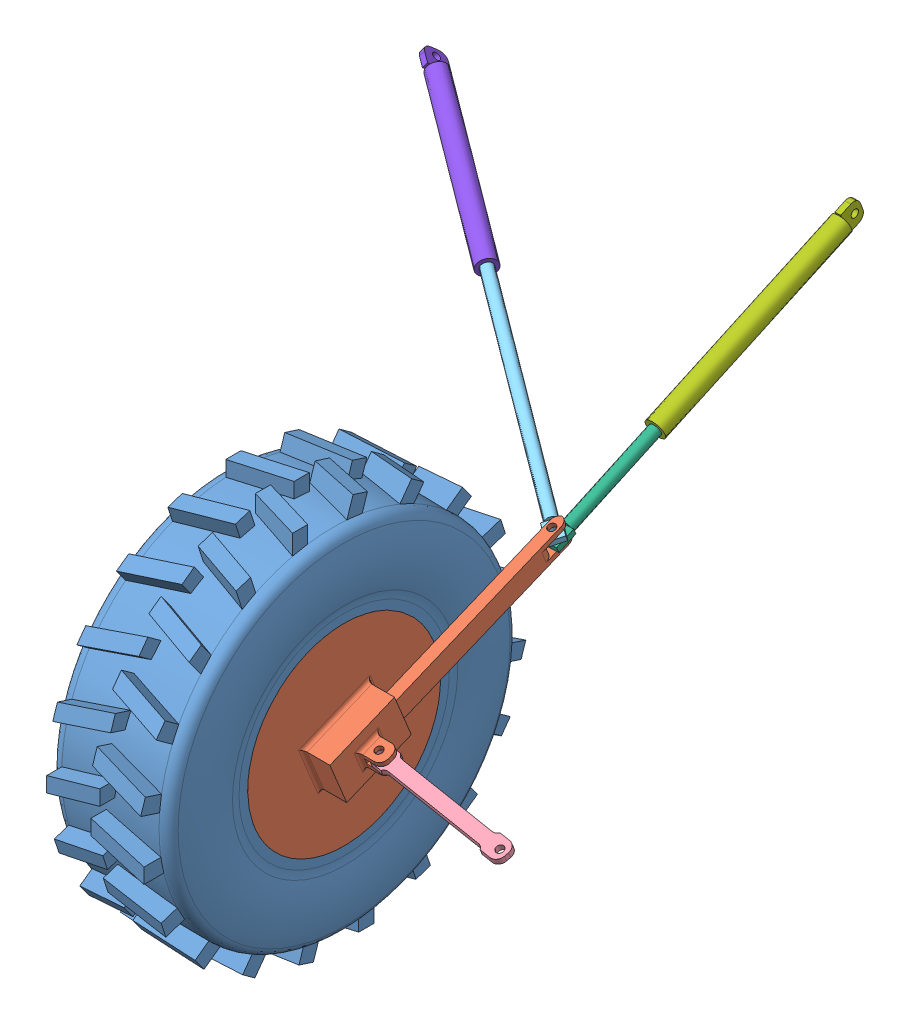
SolidWorks assembly Only tyre part assembly, configuration Default. Lengths in mm.
Overall size (145.33 108.44 186.61).
8 component instances, 8 part files, 12 mates.
Components (placement in the parent):
- Tyre-1: Tyre [Default] at (-1.433 57.6612 95.7909) size (33.63 101.74 101.74)
- Inner Rim 1-1: Inner Rim 1 [Default] at (8.2992 57.6612 95.7909) x (0 0.381849 -0.924225) z (0 -0.924225 -0.381849) size (84.64 19 50.96)
- Outer Rim Part-1: Outer Rim Part [Default] at (-17.1653 57.6612 95.7909) x (0 -0.924225 -0.381849) z (1 0 0) size (50.96 50.96 8)
- Connecting Rod 2-1: Connecting Rod 2 [Default] at (42.1511 56.0879 97.6348) x (0.991767 -0.048898 0.118352) z (0 0.924225 0.381849) size (40 5 1.5)
- Piston-1: Piston [Default] at (-40.7109 96.2103 4.4511) x (0.588692 0.308671 -0.747104) z (0 -0.924225 -0.381849) size (4 75 3)
- Piston 2-1: Piston 2 [Default] at (16.6211 100.5522 -9.9861) x (0.999581 0.011048 -0.026741) z (0 -0.924225 -0.381849) size (4 60 3)
- Piston Cover 2-1: Piston Cover 2 [Default] at (17.4575 89.5183 16.7203) x (-0.028957 -0.924157 -0.380914) z (0.999162 -0.015731 -0.037792) size (6 60 5)
- Piston Cover-1: Piston Cover [Default] at (-36.3651 95.0018 7.3761) x (-0.32369 0.602252 0.729738) z (-0.491714 -0.766004 0.414072) size (6 55 5)
Mates (geometry in assembly coordinates):
- Coincident1: coincident aligned: plane of Tyre-1 through (14.2992 85.4145 95.7909) normal (1 0 0); plane of Inner Rim 1-1 through (14.2992 57.6612 95.7909) normal (1 0 0)
- Concentric1: concentric aligned: cylinder of Tyre-1 through (-88.2849 57.6612 95.7909) axis (-1 0 0) radius 25.4808; cylinder of Inner Rim 1-1 through (14.2992 57.6612 95.7909) axis (-1 0 0) radius 25.48
- Coincident2: coincident aligned: plane of Tyre-1 through (-17.1653 85.4145 95.7909) normal (-1 0 0); plane of Outer Rim Part-1 through (-17.1653 57.6612 95.7909) normal (-1 0 0)
- Concentric2: concentric aligned: cylinder of Tyre-1 through (-88.2849 57.6612 95.7909) axis (-1 0 0) radius 25.4808; cylinder of Outer Rim Part-1 through (-11.1653 57.6612 95.7909) axis (-1 0 0) radius 25.48
- Coincident3: coincident anti-aligned: plane of Inner Rim 1-1 through (22.2992 56.6246 100.2641) normal (0 -0.924225 -0.381849); plane of Connecting Rod 2-1 through (24.2352 58.165 96.5356) normal (0 0.924225 0.381849)
- Concentric3: concentric aligned: circle of Inner Rim 1-1; circle of Connecting Rod 2-1
- Coincident5: coincident anti-aligned: plane of Inner Rim 1-1 through (8.2992 76.5997 46.024) normal (0 0.924225 0.381849); plane of Piston 2-1 through (16.358 76.9356 45.2112) normal (0 -0.924225 -0.381849)
- Concentric4: concentric anti-aligned: circle of Inner Rim 1-1; circle of Piston 2-1
- Coincident7: coincident anti-aligned: plane of Piston-1 through (18.7386 78.0404 46.4652) normal (0 -0.924225 -0.381849); plane of Piston 2-1 through (16.358 78.3219 45.784) normal (0 0.924225 0.381849)
- Concentric5: concentric aligned: circle of Inner Rim 1-1; circle of Piston-1
- Concentric6: concentric anti-aligned: cylinder of Piston 2-1 through (18.2124 79.5593 40.8249) axis (-0.028934 0.381689 -0.923838) radius 1.5; cylinder of Piston Cover 2-1 through (15.8662 110.5112 -34.0908) axis (0.028934 -0.381689 0.923838) radius 1.5
- Concentric7: concentric anti-aligned: cylinder of Piston-1 through (15.8742 80.4749 42.537) axis (-0.808358 0.224791 -0.544083) radius 1.5; cylinder of Piston Cover-1 through (-76.783 106.2414 -19.828) axis (0.808358 -0.224791 0.544083) radius 1.5
